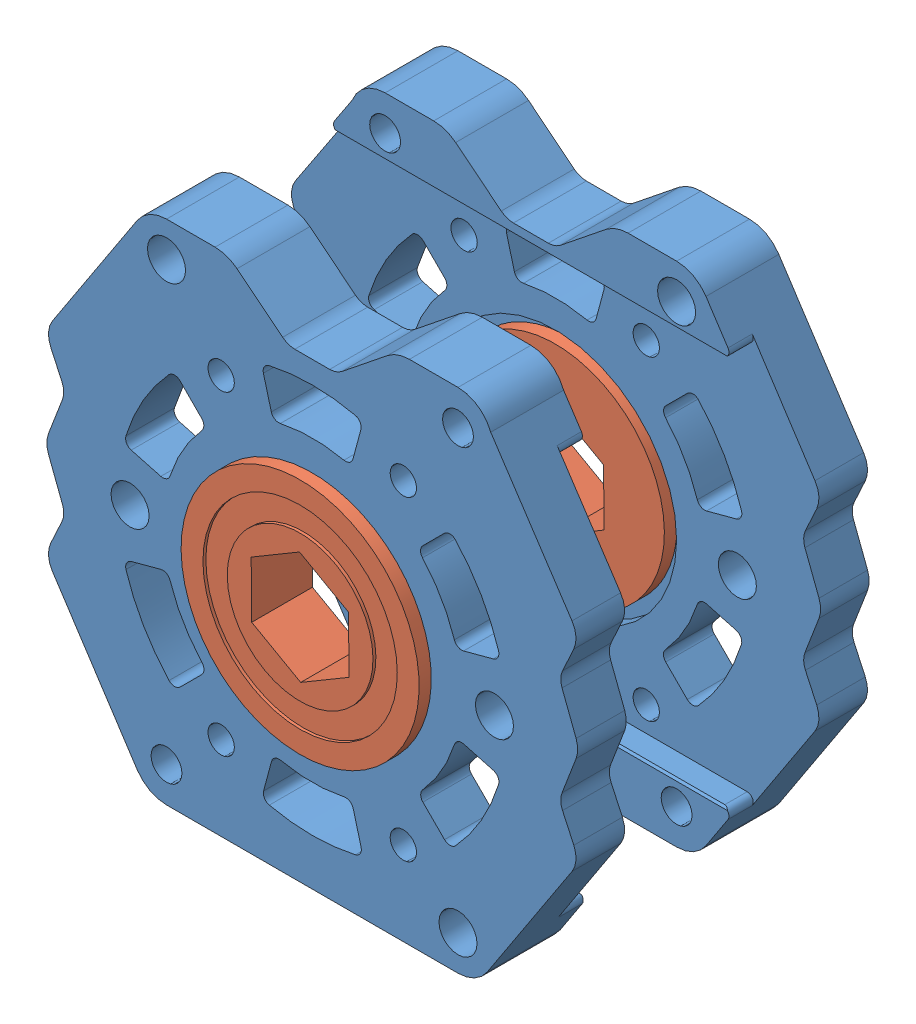
SolidWorks assembly 131-000 Bearing asm, configuration Default. Lengths in mm.
Overall size (69.4 66.32 41.27).
4 component instances, 2 part files, 12 mates.
Components (placement in the parent):
- 131-001  Bearing Block-1: 131-001  Bearing Block [Default] at origin size (69.4 66.32 9.53)
- 131-001  Bearing Block-2: 131-001  Bearing Block [Default] at (0 0 -28.575) x (-1 0 0) z (0 0 -1) size (69.4 66.32 9.53)
- 900-001 Thunder Hex Flanged Bearing-1: 900-001 Thunder Hex Flanged Bearing [Default] at (0 -1.5875 -1.5875) x (0.010404 -0.999946 0) z (-0.999946 -0.010404 0) size (31.12 7.94 31.12)
- 900-001 Thunder Hex Flanged Bearing-2: 900-001 Thunder Hex Flanged Bearing [Default] at (0 -1.5875 -26.9875) x (0.010404 -0.999946 0) z (0.999946 0.010404 0) size (31.12 7.94 31.12)
Mates (geometry in assembly coordinates):
- Distance1: distance = 25.4 mm: plane of ? through (38.0971 39.1015 43.2877) normal (0 0 -1); plane of ? through (38.0971 39.1015 17.8877) normal (0 0 1)
- Coincident2: coincident: plane of ? through (114.2971 13.638 43.2877) normal (0 1 0); plane of ? through (-38.1029 13.638 17.8877) normal (0 1 0)
- Concentric1: concentric: cylinder of ? through (38.0971 37.514 49.6377) axis (0 0 -1) radius 14.2748; cylinder of ? through (38.0971 37.514 11.5377) axis (0 0 1) radius 14.2748
- Distance2: distance = 25.4 mm: plane of 131-001  Bearing Block-1 through (0 0 -1.5875) normal (0 0 -1); plane of 131-001  Bearing Block-2 through (0 0 -26.9875) normal (0 0 1)
- Concentric2: concentric: cylinder of 131-001  Bearing Block-1 through (19.05 28.575 4.7625) axis (0 0 1) radius 2.0193; cylinder of 131-001  Bearing Block-2 through (19.05 28.575 -33.3375) axis (0 0 1) radius 2.4892
- Concentric3: concentric: cylinder of 131-001  Bearing Block-1 through (-19.05 -28.575 4.7625) axis (0 0 1) radius 2.0193; cylinder of 131-001  Bearing Block-2 through (-19.05 -28.575 -33.3375) axis (0 0 1) radius 2.4892
- Coincident4: coordinate: point of 131-001  Bearing Block-1; point of assembly
- Concentric4: concentric: cylinder of 131-001  Bearing Block-1 through (0 -1.5875 4.7625) axis (0 0 -1) radius 14.2748; cylinder of 900-001 Thunder Hex Flanged Bearing-1 through (0 -1.5875 -1.5875) axis (0 0 1) radius 14.2748
- Coincident5: coincident: plane of 131-001  Bearing Block-1 through (0 0 4.7625) normal (0 0 1); plane of 900-001 Thunder Hex Flanged Bearing-1 through (0.1619 -17.1442 4.7625) normal (0 0 -1)
- Concentric5: concentric: cylinder of 131-001  Bearing Block-2 through (0 -1.5875 -33.3375) axis (0 0 1) radius 14.2748; cylinder of 900-001 Thunder Hex Flanged Bearing-2 through (0 -1.5875 -26.9875) axis (0 0 -1) radius 14.2748
- Coincident6: coincident: plane of 131-001  Bearing Block-2 through (0 0 -33.3375) normal (0 0 -1); plane of 900-001 Thunder Hex Flanged Bearing-2 through (0.1619 -17.1442 -33.3375) normal (0 0 1)
- Parallel1: parallel: plane of 900-001 Thunder Hex Flanged Bearing-1 through (-6.3979 2.0181 -1.5875) normal (0.999946 0.010404 0); plane of 900-001 Thunder Hex Flanged Bearing-2 through (-6.3215 -5.3254 -26.9875) normal (0.999946 0.010404 0)
